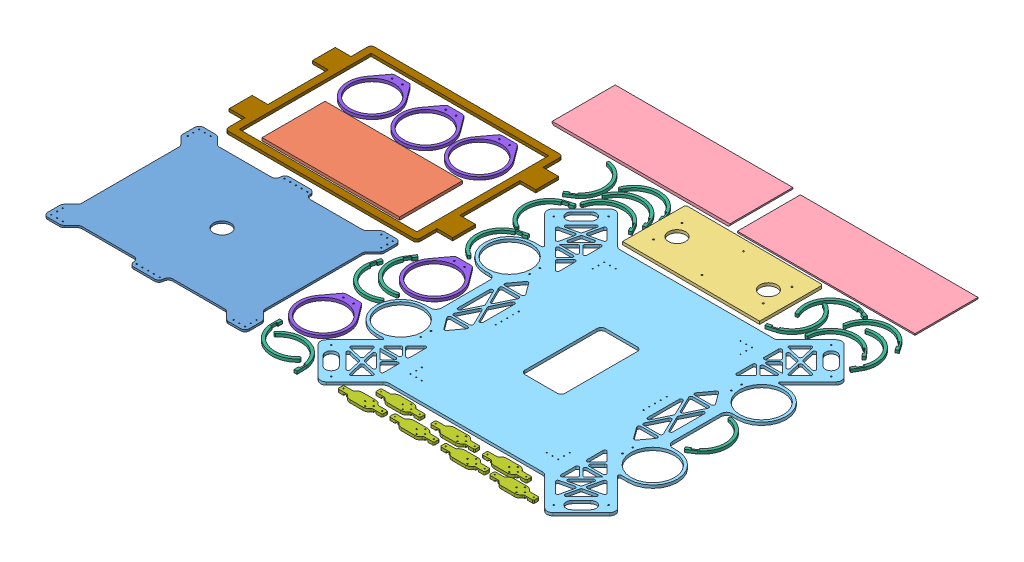
SolidWorks assembly 0.25 plate layout, configuration Default. Lengths in mm.
Overall size (1231.03 18.29 1219.2).
35 component instances, 9 part files, 27 mates.
Components (placement in the parent):
- MS-P-0001-Enclosure, Base Plate-1: MS-P-0001-Enclosure, Base Plate [Waterjet] at (-376.2104 6.35 418.9684) x (0.00021 0 1) z (0 -1 0) size (345.44 447.04 6.35)
- MS-P-0002-Enclosure, Back Plate-1: MS-P-0002-Enclosure, Back Plate [Waterjet] at (-353.0058 6.35 131.3107) x (1 0 0) z (0 -1 0) size (304.8 139.7 6.35)
- MS-P-0003-Enclosure, Front Plate-1: MS-P-0003-Enclosure, Front Plate [Default] at (246.1783 6.35 -68.3481) x (0.999994 0 0.003325) z (0 -1 0) size (304.8 139.7 6.35)
- MS-P-0004-Enclosure, Side Plate-1: MS-P-0004-Enclosure, Side Plate [Waterjet] at (-18.2292 6.35 -221.5421) x (1 0 0) z (0 -1 0) size (393.7 139.7 6.35)
- MS-P-0004-Enclosure, Side Plate-2: MS-P-0004-Enclosure, Side Plate [Waterjet] at (391.5042 0 -222.1826) x (-1 0 0) z (0 -1 0) size (393.7 139.7 6.35)
- MS-P-0008-Frame, Base Plate-1: MS-P-0008-Frame, Base Plate [Waterjet] at (270.3253 0 269.5226) x (0 0 -1) z (1 0 0) size (653.22 6.35 668.02)
- MS-P-0011-Thruster, Horizontal Guard-1: MS-P-0011-Thruster, Horizontal Guard [Default] at (543.9628 0 -54.9332) x (-0.488731 0 0.872434) z (0 -1 0) size (73.79 99.48 6.35)
- MS-P-0011-Thruster, Horizontal Guard-2: MS-P-0011-Thruster, Horizontal Guard [Default] at (-87.4715 0 539.7991) x (-0.003364 0 -0.999994) z (0 -1 0) size (73.79 99.48 6.35)
- MS-P-0012-Thruster, Horizontal Attachment Plate-5: MS-P-0012-Thruster, Horizontal Attachment Plate [Default] at (160.2467 -6.35 550.8744) x (0 0 1) z (-1 0 0) size (27.7 6.35 98.66)
- MS-P-0012-Thruster, Horizontal Attachment Plate-6: MS-P-0012-Thruster, Horizontal Attachment Plate [Default] at (109.3161 -9.525 583.2875) x (0 0 1) z (-1 0 0) size (27.7 6.35 98.66)
- MS-P-0012-Thruster, Horizontal Attachment Plate-7: MS-P-0012-Thruster, Horizontal Attachment Plate [Default] at (223.454 -6.35 583.1612) x (0 0 1) z (-1 0 0) size (27.7 6.35 98.66)
- MS-P-0012-Thruster, Horizontal Attachment Plate-8: MS-P-0012-Thruster, Horizontal Attachment Plate [Default] at (282.4068 -6.35 551.6234) x (0 0 1) z (-1 0 0) size (27.7 6.35 98.66)
- MS-P-0012-Thruster, Horizontal Attachment Plate-9: MS-P-0012-Thruster, Horizontal Attachment Plate [Default] at (336.9067 -6.35 583.8269) x (0 0 1) z (-1 0 0) size (27.7 6.35 98.66)
- MS-P-0012-Thruster, Horizontal Attachment Plate-10: MS-P-0012-Thruster, Horizontal Attachment Plate [Default] at (398.5774 -6.35 553.078) x (0 0 1) z (-1 0 0) size (27.7 6.35 98.66)
- MS-P-0012-Thruster, Horizontal Attachment Plate-11: MS-P-0012-Thruster, Horizontal Attachment Plate [Default] at (445.6625 -6.35 584.1237) x (0 0 1) z (-1 0 0) size (27.7 6.35 98.66)
- MS-P-0010-Vertical Thruster, Ring-7: MS-P-0010-Vertical Thruster, Ring [Default] at (-102.9589 -3.175 467.7374) x (0 0 1) z (1 0 0) size (120.65 6.35 109.22)
- MS-P-0011-Thruster, Horizontal Guard-10: MS-P-0011-Thruster, Horizontal Guard [Default] at (524.7854 0 -28.8276) x (0.660401 0 0.750913) z (0 -1 0) size (73.79 99.48 6.35)
- MS-P-0011-Thruster, Horizontal Guard-11: MS-P-0011-Thruster, Horizontal Guard [Default] at (-97.0256 0 325.8764) x (0.259621 0 -0.965711) z (0 -1 0) size (73.79 99.48 6.35)
- MS-P-0011-Thruster, Horizontal Guard-12: MS-P-0011-Thruster, Horizontal Guard [Default] at (-76.1692 0 291.9508) x (0.536002 0 -0.844217) z (0 -1 0) size (73.79 99.48 6.35)
- MS-P-0011-Thruster, Horizontal Guard-13: MS-P-0011-Thruster, Horizontal Guard [Default] at (21.5135 0 -21.3925) x (0.491396 0 0.870936) z (0 -1 0) size (73.79 99.48 6.35)
- MS-P-0011-Thruster, Horizontal Guard-14: MS-P-0011-Thruster, Horizontal Guard [Default] at (26.6312 0 -54.3827) x (0.358429 0 0.933557) z (0 -1 0) size (73.79 99.48 6.35)
- MS-P-0011-Thruster, Horizontal Guard-16: MS-P-0011-Thruster, Horizontal Guard [Default] at (-88.659 0 -87.7113) x (-0.835079 0 0.55013) z (0 -1 0) size (73.79 99.48 6.35)
- MS-P-0011-Thruster, Horizontal Guard-17: MS-P-0011-Thruster, Horizontal Guard [Default] at (-32.0392 0 142.3984) x (0.967095 0 -0.254415) z (0 -1 0) size (73.79 99.48 6.35)
- MS-P-0005-Enclosure, Seal Flange-1: MS-P-0005-Enclosure, Seal Flange [waterjet] at (-347.3948 2.4137 66.7927) x (0 0 -1) z (1 0 0) size (323.85 6.35 495.3)
- MS-P-0011-Thruster, Horizontal Guard-18: MS-P-0011-Thruster, Horizontal Guard [Default] at (465.9885 0 -86.3998) x (0.940607 0 0.339497) z (0 -1 0) size (73.79 99.48 6.35)
- MS-P-0011-Thruster, Horizontal Guard-19: MS-P-0011-Thruster, Horizontal Guard [Default] at (546.1787 0 -84.669) x (0.570922 0 0.821004) z (0 -1 0) size (73.79 99.48 6.35)
- MS-P-0011-Thruster, Horizontal Guard-20: MS-P-0011-Thruster, Horizontal Guard [Default] at (536.9829 0 268.3158) x (-0.835079 0 0.55013) z (0 -1 0) size (73.79 99.48 6.35)
- MS-P-0010-Vertical Thruster, Ring-10: MS-P-0010-Vertical Thruster, Ring [Default] at (-225.5967 5.5887 -0.4707) x (0 0 1) z (1 0 0) size (120.65 6.35 109.22)
- MS-P-0010-Vertical Thruster, Ring-11: MS-P-0010-Vertical Thruster, Ring [Default] at (-343.8788 3.175 -0.0468) x (0 0 1) z (1 0 0) size (120.65 6.35 109.22)
- MS-P-0010-Vertical Thruster, Ring-12: MS-P-0010-Vertical Thruster, Ring [Default] at (-462.8753 3.175 -0.3829) x (0 0 1) z (1 0 0) size (120.65 6.35 109.22)
- MS-P-0010-Vertical Thruster, Ring-13: MS-P-0010-Vertical Thruster, Ring [Default] at (-50.5052 -3.175 274.2491) x (0 0 1) z (1 0 0) size (120.65 6.35 109.22)
- MS-P-0011-Thruster, Horizontal Guard-21: MS-P-0011-Thruster, Horizontal Guard [Default] at (-81.9244 0 589.4009) x (0.03089 0 0.999523) z (0 -1 0) size (73.79 99.48 6.35)
- MS-P-0011-Thruster, Horizontal Guard-22: MS-P-0011-Thruster, Horizontal Guard [Default] at (406.5846 0 -61.1438) x (-0.96096 0 0.276686) z (0 -1 0) size (73.79 99.48 6.35)
- MS-P-0011-Thruster, Horizontal Guard-24: MS-P-0011-Thruster, Horizontal Guard [Default] at (29.2385 -3.175 -88.5658) x (0.358429 0 0.933557) z (0 -1 0) size (73.79 99.48 6.35)
- MS-P-0011-Thruster, Horizontal Guard-25: MS-P-0011-Thruster, Horizontal Guard [Default] at (-36.0349 0 33.4699) x (0.956726 0 -0.29099) z (0 -1 0) size (73.79 99.48 6.35)
Mates (geometry in assembly coordinates):
- Coincident1: coincident: plane of MS-P-0001-Enclosure, Base Plate-1 through (-376.2104 0 418.9684) normal (0 -1 0); plane of assembly through (0 0 0) normal (0 1 0)
- Coincident2: coincident: plane of MS-P-0001-Enclosure, Base Plate-1 through (-376.2104 6.35 418.9684) normal (0 1 0); plane of MS-P-0004-Enclosure, Side Plate-1 through (-18.2292 6.35 -221.5421) normal (0 1 0)
- Coincident3: coincident: plane of MS-P-0001-Enclosure, Base Plate-1 through (-376.2104 6.35 418.9684) normal (0 1 0); plane of MS-P-0002-Enclosure, Back Plate-1 through (-353.0058 6.35 131.3107) normal (0 1 0)
- Parallel2: parallel: line of MS-P-0002-Enclosure, Back Plate-1 through (-200.6058 6.35 201.1607) axis (-1 0 0); line of MS-P-0004-Enclosure, Side Plate-1 through (-215.0792 6.35 -291.3921) axis (1 0 0)
- Parallel6: parallel: line of MS-P-0004-Enclosure, Side Plate-1 through (-215.0792 6.35 -291.3921) axis (1 0 0); line of assembly
- Coincident12: coincident: plane of MS-P-0002-Enclosure, Back Plate-1 through (-353.0058 6.35 131.3107) normal (0 1 0); plane of MS-P-0003-Enclosure, Front Plate-1 through (246.1783 6.35 -68.3481) normal (0 1 0)
- Parallel7: parallel: line of MS-P-0008-Frame, Base Plate-1 through (440.3248 0 525.6049) axis (-1 0 0); line of assembly
- Coincident13: coincident: plane of MS-P-0004-Enclosure, Side Plate-2 through (391.5042 0 -222.1826) normal (0 1 0); plane of MS-P-0008-Frame, Base Plate-1 through (270.3253 0 269.5226) normal (0 1 0)
- Coincident14: coincident: plane of MS-P-0008-Frame, Base Plate-1 through (270.3253 0 269.5226) normal (0 1 0); plane of assembly through (0 0 0) normal (0 1 0)
- Parallel8: parallel: line of MS-P-0004-Enclosure, Side Plate-2 through (194.6542 0 -292.0326) axis (1 0 0); line of assembly
- Coincident17: coincident: plane of MS-P-0008-Frame, Base Plate-1 through (270.3253 0 269.5226) normal (0 1 0); plane of MS-P-0012-Thruster, Horizontal Attachment Plate-5 through (104.223 0 554.6844) normal (0 1 0)
- Parallel10: parallel: line of MS-P-0012-Thruster, Horizontal Attachment Plate-5 through (136.4925 0 564.7244) axis (1 0 0); line of assembly
- Coincident18: coincident: plane of MS-P-0008-Frame, Base Plate-1 through (270.3253 0 269.5226) normal (0 1 0); plane of MS-P-0012-Thruster, Horizontal Attachment Plate-5 through (104.223 0 554.6844) normal (0 1 0)
- Parallel11: parallel: line of MS-P-0010-Vertical Thruster, Ring-7 through (-87.7481 0 401.6974) axis (-1 0 0); line of assembly
- Coincident19: coincident: plane of MS-P-0008-Frame, Base Plate-1 through (270.3253 0 269.5226) normal (0 1 0); plane of MS-P-0011-Thruster, Horizontal Guard-1 through (543.9628 0 -54.9332) normal (0 1 0)
- Coincident20: coincident: plane of MS-P-0008-Frame, Base Plate-1 through (270.3253 0 269.5226) normal (0 1 0); plane of MS-P-0011-Thruster, Horizontal Guard-10 through (524.7854 0 -28.8276) normal (0 1 0)
- Coincident21: coincident: plane of MS-P-0008-Frame, Base Plate-1 through (270.3253 0 269.5226) normal (0 1 0); plane of MS-P-0011-Thruster, Horizontal Guard-2 through (-87.4715 0 539.7991) normal (0 1 0)
- Coincident22: coincident: plane of MS-P-0008-Frame, Base Plate-1 through (270.3253 0 269.5226) normal (0 1 0); plane of MS-P-0011-Thruster, Horizontal Guard-11 through (-97.0256 0 325.8764) normal (0 1 0)
- Coincident23: coincident: plane of MS-P-0008-Frame, Base Plate-1 through (270.3253 0 269.5226) normal (0 1 0); plane of MS-P-0011-Thruster, Horizontal Guard-12 through (-76.1692 0 291.9508) normal (0 1 0)
- Coincident25: coincident: plane of MS-P-0008-Frame, Base Plate-1 through (270.3253 0 269.5226) normal (0 1 0); plane of MS-P-0011-Thruster, Horizontal Guard-13 through (21.5135 0 -21.3925) normal (0 1 0)
- Coincident27: coincident: plane of MS-P-0008-Frame, Base Plate-1 through (270.3253 0 269.5226) normal (0 1 0); plane of MS-P-0011-Thruster, Horizontal Guard-16 through (-88.659 0 -87.7113) normal (0 1 0)
- Coincident28: coincident: plane of MS-P-0008-Frame, Base Plate-1 through (270.3253 0 269.5226) normal (0 1 0); plane of MS-P-0011-Thruster, Horizontal Guard-17 through (-32.0392 0 142.3984) normal (0 1 0)
- Coincident29: coincident: plane of MS-P-0008-Frame, Base Plate-1 through (270.3253 0 269.5226) normal (0 1 0); plane of MS-P-0011-Thruster, Horizontal Guard-18 through (465.9885 0 -86.3998) normal (0 1 0)
- Coincident31: coincident: plane of MS-P-0008-Frame, Base Plate-1 through (270.3253 0 269.5226) normal (0 1 0); plane of MS-P-0011-Thruster, Horizontal Guard-19 through (546.1787 0 -84.669) normal (0 1 0)
- Coincident32: coincident: plane of MS-P-0008-Frame, Base Plate-1 through (270.3253 0 269.5226) normal (0 1 0); plane of MS-P-0011-Thruster, Horizontal Guard-21 through (-81.9244 0 589.4009) normal (0 1 0)
- Coincident33: coincident: plane of MS-P-0008-Frame, Base Plate-1 through (270.3253 0 269.5226) normal (0 1 0); plane of MS-P-0011-Thruster, Horizontal Guard-22 through (406.5846 0 -61.1438) normal (0 1 0)
- Coincident34: coincident: plane of MS-P-0008-Frame, Base Plate-1 through (270.3253 0 269.5226) normal (0 1 0); plane of MS-P-0011-Thruster, Horizontal Guard-25 through (-36.0349 0 33.4699) normal (0 1 0)
